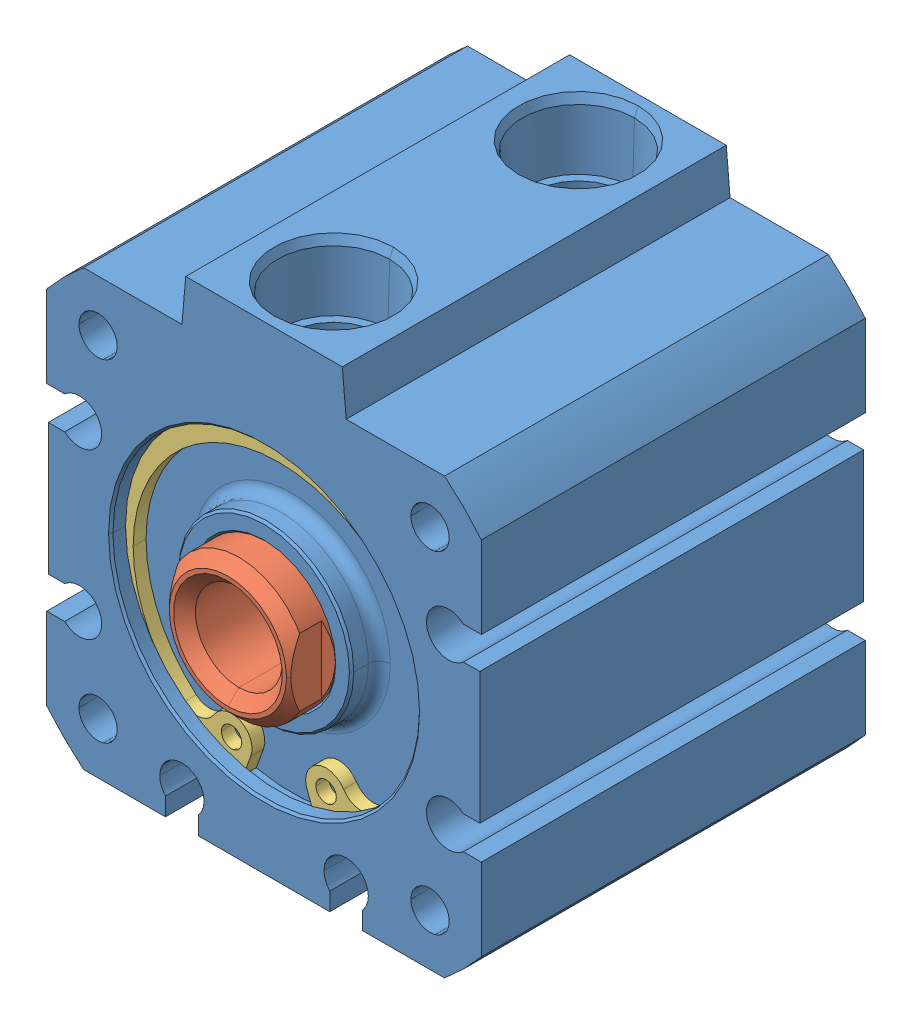
SolidWorks assembly NCQ8A106-050, configuration Default. Lengths in mm.
Overall size (39.69 43.66 51.05).
4 component instances, 3 part files, 0 mates.
Components (placement in the parent):
- NCQ8A106-050.STEP-1: NCQ8A106-050.STEP [Default] at origin size (39.69 43.66 38.35)
  - NCQ8A106-050.step_NCQ8 Tube_106A.STEP-1: NCQ8A106-050.step_NCQ8 Tube_106A.STEP [Default] at origin size (39.69 43.66 35.05)
  - NCQ8A106-050.step_NCQ8 Rod_106-LONG.STEP-1: NCQ8A106-050.step_NCQ8 Rod_106-LONG.STEP [Default] at (0 0 -8.85) x (-1 0 0) z (0 0 1) size (26.9 26.9 29.68)
  - NCQ8A106-050.step_Snap Ring_106.STEP-1: NCQ8A106-050.step_Snap Ring_106.STEP [Default] at (0 0 13.826) size (29.4 29.04 1.18)
